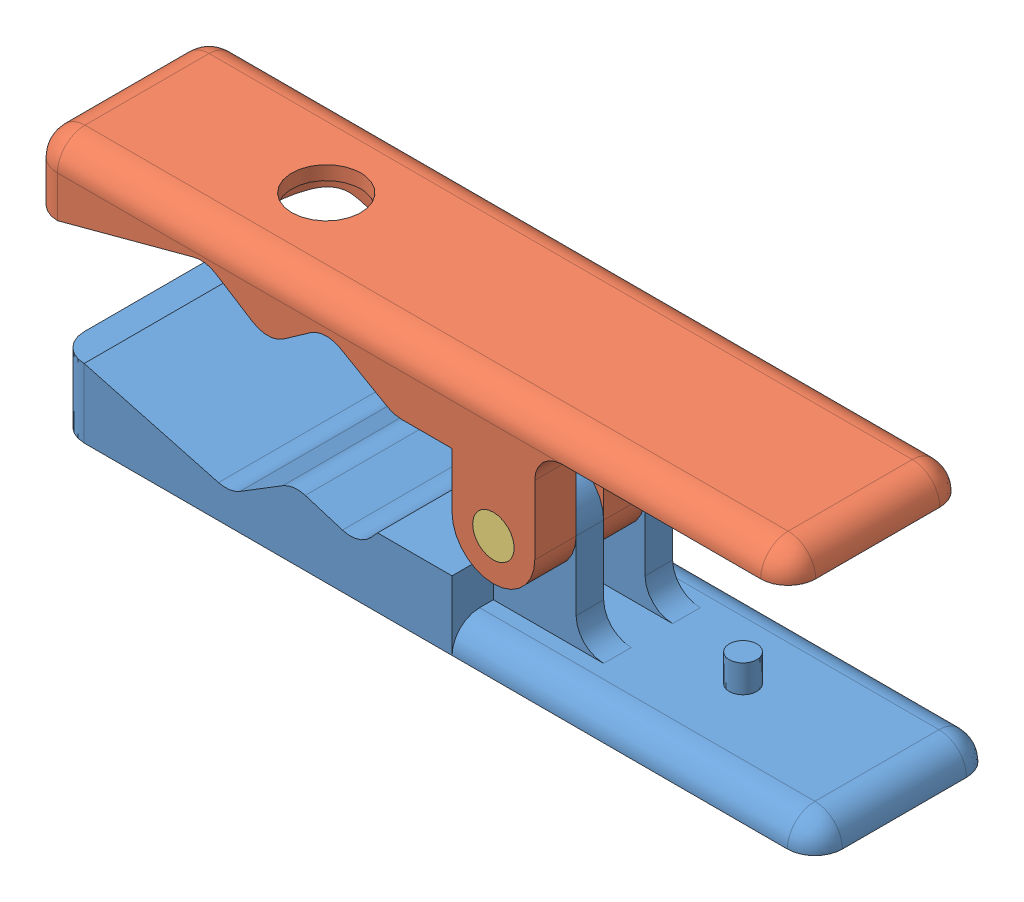
SolidWorks assembly Clamp Assembly, configuration Default. Lengths in mm.
Overall size (72.31 35.56 16.51).
3 component instances, 3 part files, 4 mates.
Components (placement in the parent):
- Clamp 1-1: Clamp 1 [Default] at (-3.6913 33.5471 71.2954) size (69.85 21.59 16.51)
- Clamp 2-1: Clamp 2 [Default] at (-6.1562 56.4071 54.7854) x (1 0 0) z (0 0 -1) size (69.85 21.59 16.51)
- Clamp pin-1: Clamp pin [Default] at (36.5419 44.9771 54.7854) size (3.81 3.81 16.51)
Mates (geometry in assembly coordinates):
- Parallel2: parallel anti-aligned: plane of Clamp 1-1 through (32.7319 36.0871 54.7854) normal (0 1 0); plane of Clamp 2-1 through (32.7319 53.8671 71.2954) normal (0 -1 0)
- Concentric1: concentric anti-aligned: circle of Clamp 1-1; circle of Clamp 2-1
- Coincident6: coincident anti-aligned: circle of Clamp 2-1; circle of Clamp pin-1
- Coincident7: coincident anti-aligned: plane of Clamp 1-1 through (-3.6913 48.7881 61.1354) normal (0 0 1); plane of Clamp 2-1 through (32.7319 41.1671 61.1354) normal (0 0 -1)
